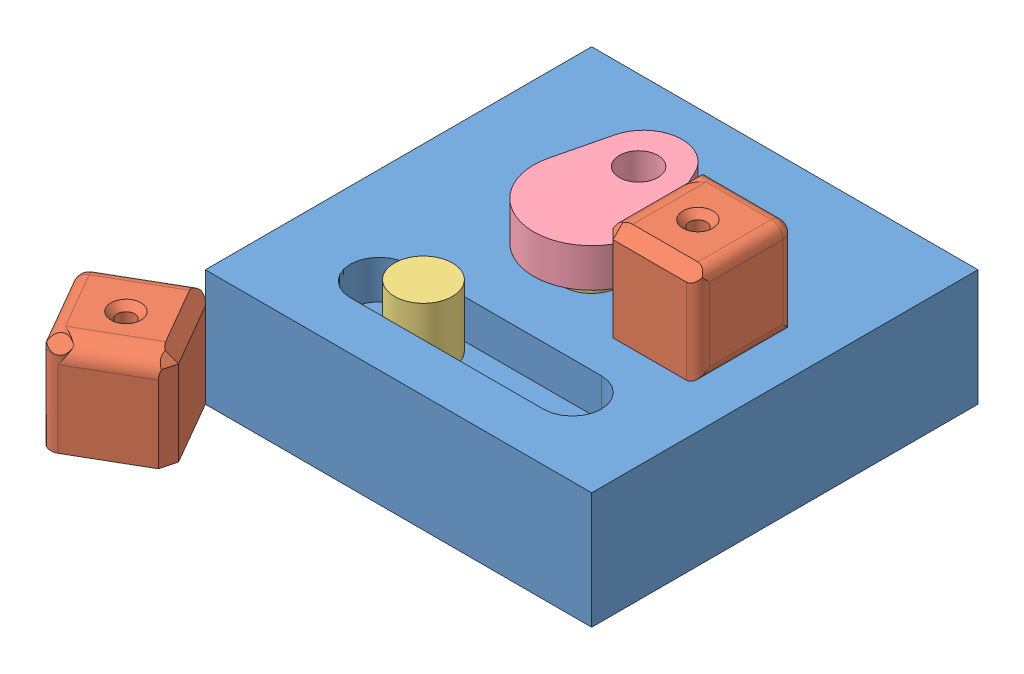
SolidWorks assembly 装配体2.1_2, configuration Default. Lengths in mm.
Overall size (123.16 55.14 131.8).
6 component instances, 4 part files, 13 mates.
Components (placement in the parent):
- 零件3.1_1-1: 零件3.1_1 [默认] at origin size (100 30.14 100)
- 零件2.1_1-2: 零件2.1_1 [默认] at (40 30.1441 12.5) x (-1 0 0) z (0 0 -1) size (25.28 25 25.01)
- 零件7^装配体2.1_2-1: 零件7^装配体2.1_2 [默认] at (-19.4344 20.1441 -33.8719) x (0.347737 0 -0.937592) z (0 1 0) size (15 15 16) (virtual)
- 零件2.1_1-3: 零件2.1_1 [默认] at (-51.5 0 47.4019) x (0.5 0 0.866025) z (-0.866025 0 0.5) size (25.28 25 25.01)
- 凸轮-1: 凸轮 [默认] at (0 46.1441 0) x (-0.101065 0 -0.99488) z (0 -1 0) size (40 30 10)
- 零件7^装配体2.1_2-2: 零件7^装配体2.1_2 [默认] at (-5.3328 20.1441 -8.177) x (0.885727 0 -0.464207) z (0 1 0) size (15 15 16) (virtual)
Mates (geometry in assembly coordinates):
- 重合7: coincident anti-aligned: plane of 零件3.1_1-1 through (0 30.1441 0) normal (0 1 0); plane of 零件2.1_1-2 through (40 30.1441 -12.5) normal (0 -1 0)
- 宽度2: width aligned: plane of 零件2.1_1-2 through (40 30.1441 12.5) normal (0 0 1); plane of 零件3.1_1-1 through (40 30.1441 -12.5) normal (0 0 -1); plane of 零件2.1_1-2 through (-50 30.1441 50) normal (0 0 1); plane of 零件3.1_1-1 through (-50 30.1441 -50) normal (0 0 -1)
- LimitDistance1: limit distance = 65 mm aligned: plane of 零件2.1_1-2 through (15 30.1441 -12.5) normal (-1 0 0); plane of 零件3.1_1-1 through (-50 30.1441 50) normal (-1 0 0)
- 重合8: coincident anti-aligned: line of 零件3.1_1-1 through (-50 30.1441 50) axis (0 -1 0); line of 零件2.1_1-3 through (-50 0 50) axis (0 1 0)
- LimitAngle1: limit planar angle = 1.047198 rad anti-aligned: plane of 零件3.1_1-1 through (-50 30.1441 50) normal (0 0 1); plane of 零件2.1_1-3 through (-51.5 0 47.4019) normal (0.866025 0 -0.5)
- 重合10: coincident aligned: plane of 零件3.1_1-1 through (0 0 0) normal (0 -1 0); plane of 零件2.1_1-3 through (-73.1506 0 59.9019) normal (0 -1 0)
- 同心3: concentric anti-aligned: cylinder of 零件3.1_1-1 through (0 20.1441 0) axis (0 1 0) radius 7.5; cylinder of 零件7^装配体2.1_2-1 through (0 36.1441 0) axis (0 -1 0) radius 7.5
- 重合11: coincident anti-aligned: plane of 零件3.1_1-1 through (0 20.1441 0) normal (0 1 0); plane of 零件7^装配体2.1_2-1 through (0 20.1441 0) normal (0 -1 0)
- 重合12: coincident anti-aligned: plane of 零件7^装配体2.1_2-1 through (0 36.1441 0) normal (0 1 0); plane of 凸轮-1 through (0 36.1441 0) normal (0 -1 0)
- 同心4: concentric anti-aligned: cylinder of 零件7^装配体2.1_2-1 through (0 36.1441 0) axis (0 -1 0) radius 7.5; cylinder of 凸轮-1 through (0 36.1441 0) axis (0 1 0) radius 15
- 凸轮配合相切1: cam tangent anti-aligned: cylinder of 凸轮-1 through (-1.516 36.1441 -14.9232) axis (0 1 0) radius 10; plane of 零件2.1_1-2 through (15 30.1441 -12.5) normal (-1 0 0)
- 重合13: coincident anti-aligned: plane of 零件3.1_1-1 through (-25 20.1441 30) normal (0 1 0); plane of 零件7^装配体2.1_2-2 through (-13.5497 20.1441 30) normal (0 -1 0)
- 槽口1: slot anti-aligned: cylinder of 零件7^装配体2.1_2-2 through (-13.5497 36.1441 30) axis (0 -1 0) radius 7.5; plane of 零件3.1_1-1 through (-25 20.1441 22.5) normal (0 0 1); cylinder of 零件3.1_1-1 through (-25 20.1441 30) axis (0 1 0) radius 7.5
